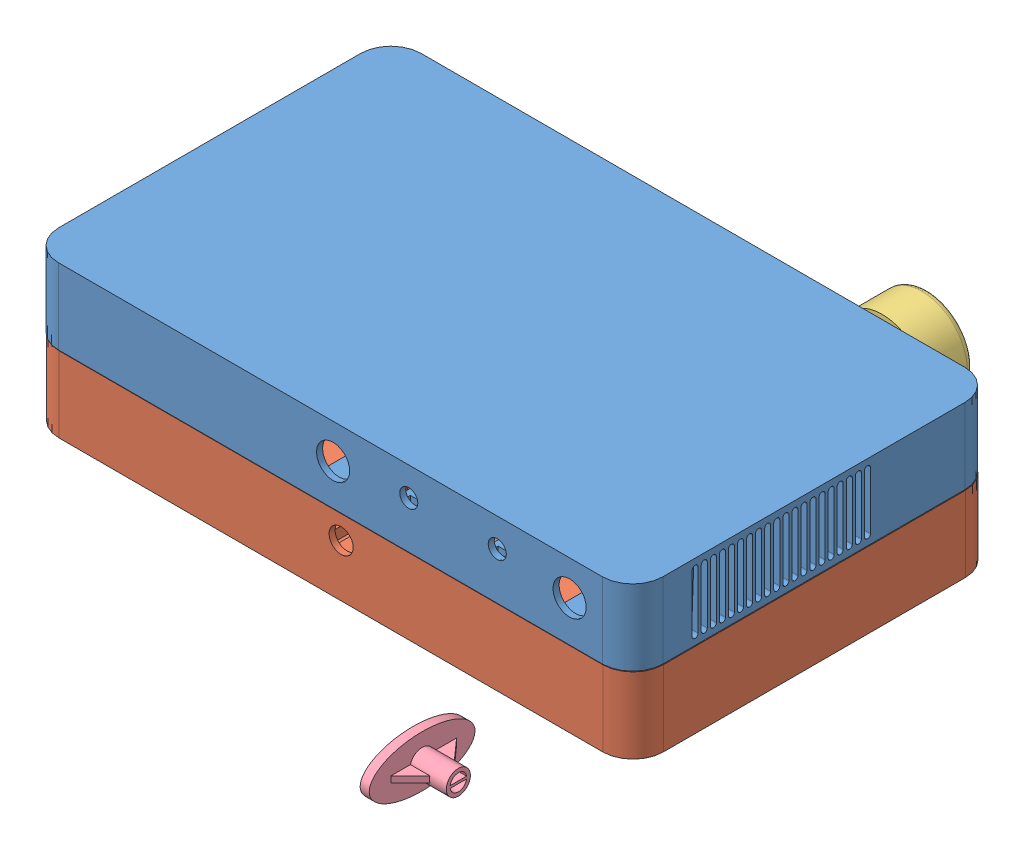
SolidWorks assembly Assem2, configuration Default. Lengths in mm.
Overall size (200.07 92.26 164.42).
4 component instances, 4 part files, 0 mates.
Components (placement in the parent):
- Body6-1: Body6 [Default] at (42.4541 108.4954 193.7931) x (1 0 0) z (0 1 0) size (200 121.16 39.22)
- Body10-1: Body10 [Default] at (42.8399 108.9337 194.6266) x (1 0 0) z (0 1 0) size (200 120 28)
- Part1-1: Part1 [Default] at (104.3323 123.8953 120.3952) size (30 30 18)
- servocap-1: servocap [Default] at (82.7017 65.2745 124.633) x (0 0 -1) z (1 0 0) size (35 17 15)
